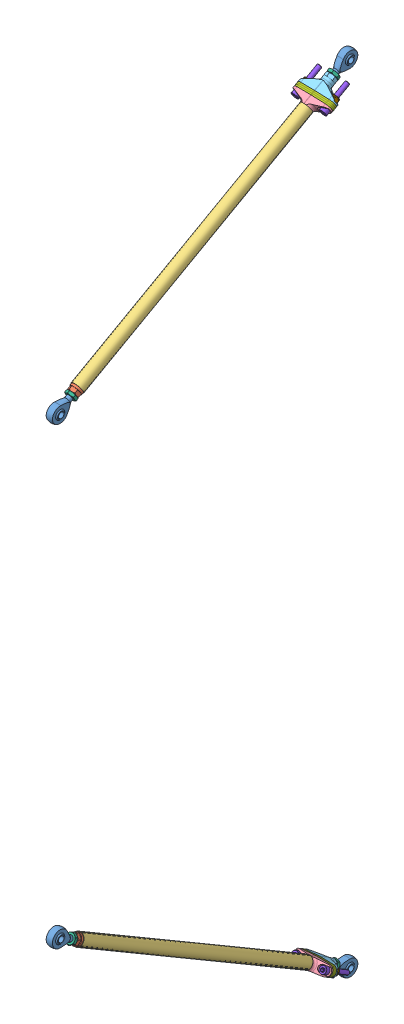
SolidWorks assembly PUTM-S-SF-DS-Pushrod, configuration Domyślna. Lengths in mm.
Overall size (55.39 1164.47 444.32).
30 component instances, 9 part files, 27 mates.
Components (placement in the parent):
- PUTM-S-rodend-1: PUTM-S-rodend [8mm] at (16.1142 544.6228 177.5261) x (0.999845 -0.01736 0.002913) z (0.013544 0.864372 0.502671) size (12 54 24)
- PUTM-S-Insert-M8-1: PUTM-S-Insert-M8 [M8] at (11.5338 341.9347 526.1831) x (0.011357 0.502552 -0.864472) z (0.972059 0.197164 0.127389) size (38.3 16.51 15.5)
- PUTM-S-SF-DS-1: PUTM-S-SF-DS [Domyślna] at (15.8235 531.7571 199.6573) x (0.870419 0.420563 0.255925) z (-0.011357 -0.502552 0.864472) size (16.7 16.7 375.94)
- PUTM-S-SF-DS-Insert-shims-1: PUTM-S-SF-DS-Insert-shims [Domyślna] at (15.9689 538.1934 188.5858) x (-0.999648 0.02645 0.002244) z (0.023993 0.864142 0.502675) size (54 51.59 16.38)
- PUTM-S-SF-DS-Insert-shims-2-1: PUTM-S-SF-DS-Insert-shims-2 [M8] at (16.037 541.2087 183.399) x (0.999648 -0.02645 -0.002244) z (0.023993 0.864142 0.502675) size (54 25 22.85)
- PUTM-S-DS-DIN-EN-ISO-4035-1: PUTM-S-DS-DIN-EN-ISO-4035 [M8_low] at (16.3664 555.7827 158.3293) x (0.730738 0.585963 0.350243) z (-0.011357 -0.502552 0.864472) size (13 15.01 4)
- PUTM-S-SF-DS-Shims-1: PUTM-S-SF-DS-Shims [2mm] at (15.9916 539.1985 186.8569) x (0.999648 -0.02645 -0.002244) z (-0.011357 -0.502552 0.864472) size (54 15.5 2)
- PUTM-S-SF-DS-Shims-2: PUTM-S-SF-DS-Shims [2mm] at (16.0143 540.2036 185.1279) x (0.999648 -0.02645 -0.002244) z (-0.011357 -0.502552 0.864472) size (54 15.5 2)
- PUTM-S-SF-DS-Shims-3: PUTM-S-SF-DS-Shims [2mm] at (16.037 541.2087 183.399) x (0.999648 -0.02645 -0.002244) z (-0.011357 -0.502552 0.864472) size (54 15.5 2)
- PUTM-S-rodend-2: PUTM-S-rodend [8mm] at (11.6624 347.6215 516.4009) x (0.999727 -0.023347 -0.000309) z (-0.020338 -0.864233 -0.50268) size (12 54 24)
- PUTM-S-DS-DIN-EN-ISO-4035-2: PUTM-S-DS-DIN-EN-ISO-4035 [M8_low] at (11.4737 339.2712 530.7648) x (0.999931 -0.003061 0.011357) z (-0.011357 -0.502552 0.864472) size (13 15.01 4)
- PUTM-FT-FABORY_ISO912-2: PUTM-FT-FABORY_ISO912 [M6x35 [07071.060.035]] at (35.871 533.644 195.4567) x (-0.011357 -0.502552 0.864472) z (-0.998923 -0.033187 -0.032416) size (41 10 10)
- PUTM-FT-FABORY_ISO912-3: PUTM-FT-FABORY_ISO912 [M6x35 [07071.060.035]] at (-4.1149 534.702 195.5465) x (-0.011357 -0.502552 0.864472) z (0.178681 -0.851633 -0.492741) size (41 10 10)
- PUTM-FT-FABORY_DIN985-1: PUTM-FT-FABORY_DIN985 [M6 [12348.060.001]] at (36.0527 541.6848 181.6251) x (0.999697 -0.024571 -0.001151) z (0.011357 0.502552 -0.864472) size (11.9 10.35 6.18)
- PUTM-FT-FABORY_DIN985-2: PUTM-FT-FABORY_DIN985 [M6 [12348.060.001]] at (-3.9332 542.7428 181.7149) x (0.981398 -0.171296 -0.086688) z (0.011357 0.502552 -0.864472) size (11.9 10.35 6.18)
- PUTM-FT-FABORY_DIN985-3: PUTM-FT-FABORY_DIN985 [M6 [12348.060.001]] at (-3.9332 -542.7428 181.7149) x (-0.981398 -0.171296 0.086688) z (0.011357 -0.502552 -0.864472) size (11.9 10.35 6.18)
- PUTM-FT-FABORY_ISO912-4: PUTM-FT-FABORY_ISO912 [M6x35 [07071.060.035]] at (-4.1149 -534.702 195.5465) x (-0.011357 0.502552 0.864472) z (-0.178681 -0.851633 0.492741) size (41 10 10)
- PUTM-S-rodend-3: PUTM-S-rodend [8mm] at (11.6624 -347.6215 516.4009) x (0.999727 0.023347 -0.000309) z (0.020338 -0.864233 0.50268) size (12 54 24)
- PUTM-S-SF-DS-Shims-4: PUTM-S-SF-DS-Shims [2mm] at (15.9916 -539.1985 186.8569) x (0.999648 0.02645 -0.002244) z (0.011357 -0.502552 -0.864472) size (54 15.5 2)
- PUTM-S-SF-DS-Shims-5: PUTM-S-SF-DS-Shims [2mm] at (15.9689 -538.1934 188.5858) x (0.999648 0.02645 -0.002244) z (0.011357 -0.502552 -0.864472) size (54 15.5 2)
- PUTM-S-SF-DS-Insert-shims-2-2: PUTM-S-SF-DS-Insert-shims-2 [M8] at (16.037 -541.2087 183.399) x (0.999648 0.02645 -0.002244) z (-0.023993 0.864142 -0.502675) size (54 25 22.85)
- PUTM-S-Insert-M8-2: PUTM-S-Insert-M8 [M8] at (11.5338 -341.9347 526.1831) x (0.011357 -0.502552 -0.864472) z (-0.972059 0.197164 -0.127389) size (38.3 16.51 15.5)
- PUTM-S-SF-DS-Insert-shims-2: PUTM-S-SF-DS-Insert-shims [Domyślna] at (15.9689 -538.1934 188.5858) x (-0.999648 -0.02645 0.002244) z (-0.023993 0.864142 -0.502675) size (54 51.59 16.38)
- PUTM-FT-FABORY_DIN985-4: PUTM-FT-FABORY_DIN985 [M6 [12348.060.001]] at (36.0527 -541.6848 181.6251) x (-0.999697 -0.024571 0.001151) z (0.011357 -0.502552 -0.864472) size (11.9 10.35 6.18)
- PUTM-S-DS-DIN-EN-ISO-4035-3: PUTM-S-DS-DIN-EN-ISO-4035 [M8_low] at (11.4282 -337.261 534.2227) x (0.999931 0.003061 0.011357) z (0.011357 -0.502552 -0.864472) size (13 15.01 4)
- PUTM-S-SF-DS-Shims-6: PUTM-S-SF-DS-Shims [2mm] at (16.0143 -540.2036 185.1279) x (0.999648 0.02645 -0.002244) z (0.011357 -0.502552 -0.864472) size (54 15.5 2)
- PUTM-S-SF-DS-2: PUTM-S-SF-DS [Domyślna] at (11.5818 -344.0547 522.5364) x (0.870419 -0.420563 0.255925) z (0.011357 -0.502552 -0.864472) size (16.7 16.7 375.94)
- PUTM-FT-FABORY_ISO912-5: PUTM-FT-FABORY_ISO912 [M6x35 [07071.060.035]] at (35.871 -533.644 195.4567) x (-0.011357 0.502552 0.864472) z (0.998923 -0.033187 0.032416) size (41 10 10)
- PUTM-S-rodend-4: PUTM-S-rodend [8mm] at (16.1142 -544.6228 177.5261) x (0.999845 0.01736 0.002913) z (-0.013544 0.864372 -0.502671) size (12 54 24)
- PUTM-S-DS-DIN-EN-ISO-4035-4: PUTM-S-DS-DIN-EN-ISO-4035 [M8_low] at (16.321 -553.7725 161.7872) x (0.730738 -0.585963 0.350243) z (0.011357 -0.502552 -0.864472) size (13 15.01 4)
Mates (geometry in assembly coordinates):
- Koncentryczne5: concentric aligned: cylinder of PUTM-S-Insert-M8-1 through (11.5679 343.4424 523.5897) axis (-0.011357 -0.502552 0.864472) radius 6.3; cylinder of PUTM-S-SF-DS-1 through (11.2997 331.5734 544.0063) axis (-0.011357 -0.502552 0.864472) radius 6.35
- Wspólnie5: coincident anti-aligned: plane of PUTM-S-Insert-M8-1 through (10.0791 348.7876 526.6775) normal (0.011357 0.502552 -0.864472); plane of PUTM-S-SF-DS-1 through (10.0791 348.7876 526.6775) normal (-0.011357 -0.502552 0.864472)
- Koncentryczne8: concentric anti-aligned: cone of PUTM-S-rodend-1 through (16.3981 557.1864 155.9147) axis (-0.011357 -0.502552 0.864472); cylinder of PUTM-S-SF-DS-Insert-shims-2-1 through (16.037 541.2087 183.399) axis (0.011357 0.502552 -0.864472) radius 3.594
- Koncentryczne9: concentric anti-aligned: cylinder of PUTM-S-SF-DS-Insert-shims-1 through (35.9619 537.6644 188.5409) axis (-0.011357 -0.502552 0.864472) radius 3; cylinder of PUTM-S-SF-DS-Insert-shims-2-1 through (36.03 540.6797 183.3541) axis (0.011357 0.502552 -0.864472) radius 3
- Koncentryczne10: concentric anti-aligned: cone of PUTM-S-rodend-1 through (16.3981 557.1864 155.9147) axis (-0.011357 -0.502552 0.864472); cylinder of PUTM-S-DS-DIN-EN-ISO-4035-1 through (16.321 553.7725 161.7872) axis (0.011357 0.502552 -0.864472) radius 4
- Wspólnie7: coincident aligned: circle of PUTM-S-SF-DS-Insert-shims-2-1; plane of PUTM-S-DS-DIN-EN-ISO-4035-1 through (16.321 553.7725 161.7872) normal (-0.011357 -0.502552 0.864472)
- Koncentryczne11: concentric anti-aligned: cylinder of PUTM-S-SF-DS-Insert-shims-1 through (-4.024 538.7224 188.6307) axis (-0.011357 -0.502552 0.864472) radius 3; cylinder of PUTM-S-SF-DS-Shims-1 through (-4.024 538.7224 188.6307) axis (0.011357 0.502552 -0.864472) radius 3
- Koncentryczne12: concentric anti-aligned: cylinder of PUTM-S-SF-DS-Insert-shims-1 through (35.9619 537.6644 188.5409) axis (-0.011357 -0.502552 0.864472) radius 3; cylinder of PUTM-S-SF-DS-Shims-1 through (35.9619 537.6644 188.5409) axis (0.011357 0.502552 -0.864472) radius 3
- Wspólnie8: coincident anti-aligned: plane of PUTM-S-SF-DS-Insert-shims-1 through (15.9689 538.1934 188.5858) normal (0.011357 0.502552 -0.864472); plane of PUTM-S-SF-DS-Shims-1 through (15.9689 538.1934 188.5858) normal (-0.011357 -0.502552 0.864472)
- Koncentryczne13: concentric aligned: cylinder of PUTM-S-SF-DS-Shims-1 through (35.9619 537.6644 188.5409) axis (0.011357 0.502552 -0.864472) radius 3; cylinder of PUTM-S-SF-DS-Shims-2 through (35.9846 538.6695 186.812) axis (0.011357 0.502552 -0.864472) radius 3
- Koncentryczne14: concentric aligned: cylinder of PUTM-S-SF-DS-Shims-1 through (-4.024 538.7224 188.6307) axis (0.011357 0.502552 -0.864472) radius 3; cylinder of PUTM-S-SF-DS-Shims-2 through (-4.0013 539.7275 186.9017) axis (0.011357 0.502552 -0.864472) radius 3
- Wspólnie9: coincident anti-aligned: plane of PUTM-S-SF-DS-Shims-1 through (15.9916 539.1985 186.8569) normal (0.011357 0.502552 -0.864472); plane of PUTM-S-SF-DS-Shims-2 through (15.9916 539.1985 186.8569) normal (-0.011357 -0.502552 0.864472)
- Koncentryczne15: concentric aligned: cylinder of PUTM-S-SF-DS-Shims-2 through (35.9846 538.6695 186.812) axis (0.011357 0.502552 -0.864472) radius 3; cylinder of PUTM-S-SF-DS-Shims-3 through (36.0073 539.6746 185.083) axis (0.011357 0.502552 -0.864472) radius 3
- Koncentryczne16: concentric aligned: cylinder of PUTM-S-SF-DS-Shims-2 through (-4.0013 539.7275 186.9017) axis (0.011357 0.502552 -0.864472) radius 3; cylinder of PUTM-S-SF-DS-Shims-3 through (-3.9786 540.7326 185.1728) axis (0.011357 0.502552 -0.864472) radius 3
- Wspólnie10: coincident anti-aligned: plane of PUTM-S-SF-DS-Shims-2 through (16.0143 540.2036 185.1279) normal (0.011357 0.502552 -0.864472); plane of PUTM-S-SF-DS-Shims-3 through (16.0143 540.2036 185.1279) normal (-0.011357 -0.502552 0.864472)
- Wspólnie11: coincident anti-aligned: plane of PUTM-S-SF-DS-Insert-shims-2-1 through (16.037 541.2087 183.399) normal (-0.011357 -0.502552 0.864472); plane of PUTM-S-SF-DS-Shims-3 through (16.037 541.2087 183.399) normal (0.011357 0.502552 -0.864472)
- Koncentryczne17: concentric anti-aligned: cylinder of PUTM-S-Insert-M8-1 through (11.5338 341.9347 526.1831) axis (-0.011357 -0.502552 0.864472) radius 4; cone of PUTM-S-rodend-2 through (11.3784 335.058 538.0123) axis (0.011357 0.502552 -0.864472)
- Koncentryczne19: concentric aligned: cone of PUTM-S-rodend-2 through (11.3784 335.058 538.0123) axis (0.011357 0.502552 -0.864472); cylinder of PUTM-S-DS-DIN-EN-ISO-4035-2 through (11.4282 337.261 534.2227) axis (0.011357 0.502552 -0.864472) radius 4
- Wspólnie13: coincident anti-aligned: plane of PUTM-S-Insert-M8-1 through (11.4737 339.2712 530.7648) normal (-0.011357 -0.502552 0.864472); plane of PUTM-S-DS-DIN-EN-ISO-4035-2 through (11.4737 339.2712 530.7648) normal (0.011357 0.502552 -0.864472)
- Koncentryczne20: concentric anti-aligned: cylinder of PUTM-S-SF-DS-Insert-shims-1 through (-4.024 538.7224 188.6307) axis (-0.011357 -0.502552 0.864472) radius 3; cylinder of PUTM-FT-FABORY_ISO912-3 through (-2.7162 596.5957 89.0789) axis (0.011357 0.502552 -0.864472) radius 3
- Wspólnie14: coincident anti-aligned: plane of PUTM-S-SF-DS-Insert-shims-1 through (-1.5476 537.6512 190.354) normal (-0.011357 -0.502552 0.864472); plane of PUTM-FT-FABORY_ISO912-3 through (-8.966 536.9729 189.8623) normal (0.011357 0.502552 -0.864472)
- Koncentryczne21: concentric anti-aligned: cylinder of PUTM-S-SF-DS-Insert-shims-1 through (35.9619 537.6644 188.5409) axis (-0.011357 -0.502552 0.864472) radius 3; cylinder of PUTM-FT-FABORY_ISO912-2 through (37.2697 595.5377 88.9892) axis (0.011357 0.502552 -0.864472) radius 3
- Wspólnie15: coincident anti-aligned: plane of PUTM-S-SF-DS-Insert-shims-1 through (33.44 536.7254 190.2755) normal (-0.011357 -0.502552 0.864472); plane of PUTM-FT-FABORY_ISO912-2 through (35.7142 540.9788 192.778) normal (0.011357 0.502552 -0.864472)
- Koncentryczne22: concentric anti-aligned: cylinder of PUTM-FT-FABORY_ISO912-2 through (37.2697 595.5377 88.9892) axis (0.011357 0.502552 -0.864472) radius 3; cylinder of PUTM-FT-FABORY_DIN985-1 through (36.0981 543.695 178.1673) axis (-0.011357 -0.502552 0.864472) radius 3
- Wspólnie16: coincident anti-aligned: plane of PUTM-S-SF-DS-Insert-shims-2-1 through (33.5536 541.7509 181.6308) normal (0.011357 0.502552 -0.864472); plane of PUTM-FT-FABORY_DIN985-1 through (36.0527 541.6848 181.6251) normal (-0.011357 -0.502552 0.864472)
- Koncentryczne23: concentric anti-aligned: cylinder of PUTM-FT-FABORY_ISO912-3 through (-2.7162 596.5957 89.0789) axis (0.011357 0.502552 -0.864472) radius 3; cylinder of PUTM-FT-FABORY_DIN985-2 through (-3.8878 544.753 178.257) axis (-0.011357 -0.502552 0.864472) radius 3
- Wspólnie17: coincident anti-aligned: plane of PUTM-S-SF-DS-Insert-shims-2-1 through (-1.4341 542.6767 181.7093) normal (0.011357 0.502552 -0.864472); plane of PUTM-FT-FABORY_DIN985-2 through (-3.9332 542.7428 181.7149) normal (-0.011357 -0.502552 0.864472)
